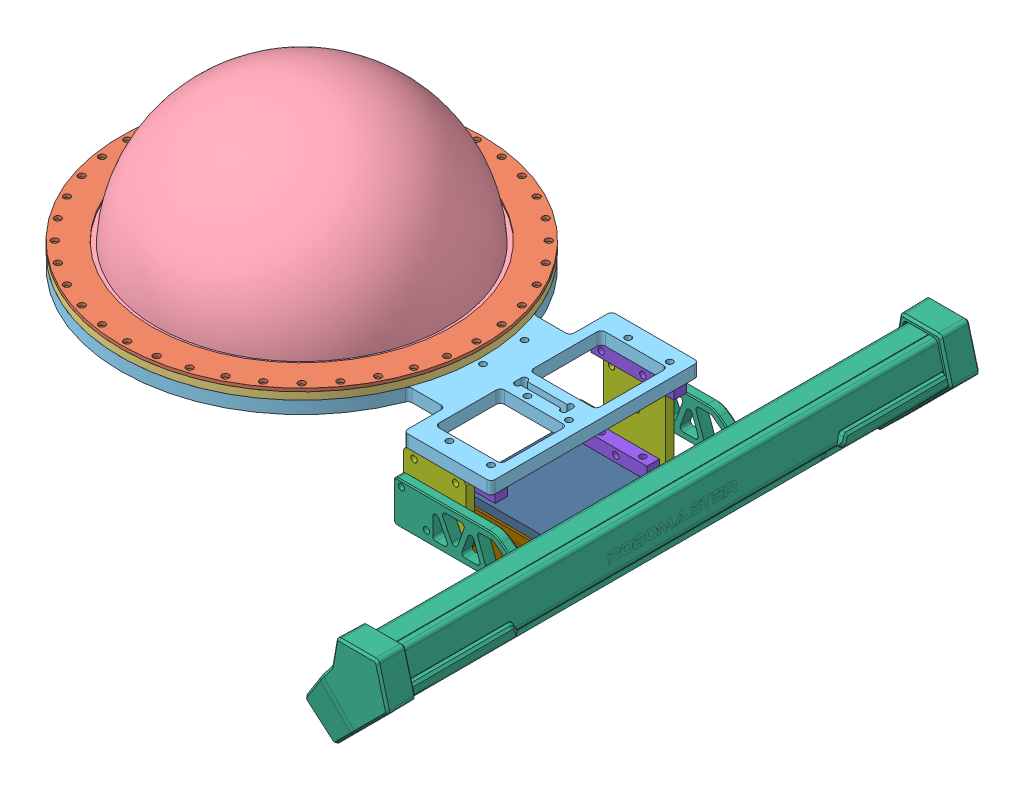
SolidWorks assembly MID-360模块, configuration 默认. Lengths in mm.
Overall size (293.47 159.5 285.15).
14 component instances, 11 part files, 41 mates.
Components (placement in the parent):
- pc球壳-1: pc球壳 [默认] at origin size (187 95 187) (hidden)
- mid-360-asm-1: mid-360-asm [默认] at (0 20.9171 0) size (72.74 69.72 66.83)
- pc球壳扣板-1: pc球壳扣板 [默认] x (0 0 -1) z (0 -1 0) size (174 174 1.5)
- pc球壳外挡圈-1: pc球壳外挡圈 [默认] at (0 -5 0) x (0.309017 0 -0.951057) z (0 1 0) size (174 174 3.5)
- 半球保护-100mm-1: 半球保护-100mm [默认] at (0 -5 0) x (0.993505 0 0.113788) z (0.113788 0 -0.993505) size (160 70 160)
- 360安装板-1: 360安装板 [默认] at (0 -5 0) x (1 0 0) z (0 -1 0) size (228 174 6)
- RM2019裁判系统灯条模块LI01-1: RM2019裁判系统灯条模块LI01 [默认] at (139.0893 -65.2494 -118.7555) x (0 0 -1) z (0 -1 0) size (285.15 84.96 50.25)
- 灯条安装板-1: 灯条安装板 [灯条安装] at (114 -26 48) size (30 30 4)
- 转接件上交-1: 转接件上交 [默认] at (99 -11 46) x (0 -1 0) z (1 0 0) size (6 6 40)
- 转接件上交-2: 转接件上交 [默认] at (99 -11 -40) x (0 -1 0) z (1 0 0) size (6 6 40)
- 灯条安装板-2: 灯条安装板 [uwb支撑] at (114 -26 -48) size (46 50 4)
- RM2019裁判系统定位模块UW01-1: RM2019裁判系统定位模块UW01 [默认] at (26.217 -93.7493 -13.6897) x (1 0 0) z (0 0 -1) size (45.56 33.5 81.86)
- uwb安装板-1: uwb安装板 [默认] at (106 -57 -19) x (1 0 0) z (0 -1 0) size (46 54 4)
- 转接件上交-3: 转接件上交 [默认] at (86 -51 -40) x (0 -1 0) z (1 0 0) size (6 6 40)
Mates (geometry in assembly coordinates):
- 同心1: concentric aligned: cylinder of pc球壳-1 through (0 0 0) axis (0 -1 0) radius 93.5; cylinder of pc球壳外挡圈-1 through (0 -1.5 0) axis (0 -1 0) radius 81
- 同心2: concentric anti-aligned: cylinder of pc球壳扣板-1 through (0 -1.5 0) axis (0 1 0) radius 72; cylinder of pc球壳外挡圈-1 through (0 -1.5 0) axis (0 -1 0) radius 87
- 重合3: coincident aligned: plane of mid-360-asm-1 through (0 -5 0) normal (0 -1 0); plane of pc球壳外挡圈-1 through (0 -5 0) normal (0 -1 0)
- 对称1: symmetric aligned: plane of mid-360-asm-1 through (-32.1003 8.6891 0) normal (0.999391 -0.034899 0); plane of mid-360-asm-1 through (32.1003 8.6891 0) normal (-0.999391 -0.034899 0)
- 对称2: symmetric aligned: plane of mid-360-asm-1 through (0 -3.0251 32.338) normal (0 -0.034899 0.999391); plane of mid-360-asm-1 through (0 -3.0251 -32.338) normal (0 -0.034899 -0.999391)
- 同心3: concentric: cylinder of pc球壳扣板-1 through (34.9459 9.0619 -73.0738) axis (0 1 0) radius 1.6; cylinder of pc球壳外挡圈-1 through (48.7107 3.5 -85.6126) axis (0 -1 0) radius 1.6
- 同心68: concentric: cylinder of pc球壳外挡圈-1 through (0 -1.5 0) axis (0 -1 0) radius 87; sphere of 半球保护-100mm-1
- 重合75: coincident aligned: plane of mid-360-asm-1 through (0 -5 0) normal (0 -1 0); plane of 半球保护-100mm-1 through (0 -5 0) normal (0 -1 0)
- 重合76: coincident anti-aligned: plane of pc球壳扣板-1 through (0 -1.5 0) normal (0 -1 0); plane of pc球壳外挡圈-1 through (0 -1.5 0) normal (0 1 0)
- 同心69: concentric anti-aligned: cylinder of pc球壳扣板-1 through (13.1405 -1.5 -82.9658) axis (0 1 0) radius 1.6; cylinder of pc球壳外挡圈-1 through (13.1405 -1.5 -82.9658) axis (0 -1 0) radius 1.6
- 重合77: coincident anti-aligned: plane of mid-360-asm-1 through (0 -5 0) normal (0 -1 0); plane of 360安装板-1 through (0 -5 0) normal (0 1 0)
- 同心70: concentric anti-aligned: cylinder of mid-360-asm-1 through (24 0.096 18) axis (0 -1 0) radius 1.25; cylinder of 360安装板-1 through (24 -11 18) axis (0 1 0) radius 1.55
- 同心71: concentric aligned: cone of mid-360-asm-1 through (24 -5 -18) axis (0 1 0); cylinder of 360安装板-1 through (24 -11 -18) axis (0 1 0) radius 1.55
- 平行1: parallel aligned: plane of 360安装板-1 through (0 -5 0) normal (0 1 0); plane of RM2019裁判系统灯条模块LI01-1 through (101 -21 54.5) normal (0 1 0)
- 宽度1: width aligned: plane of RM2019裁判系统灯条模块LI01-1 through (99.5 -43.8936 55) normal (0 0 1); plane of RM2019裁判系统灯条模块LI01-1 through (99.8 -43.8936 -55) normal (0 0 -1); plane of 360安装板-1 through (137 -117.9766 50) normal (0 0 1); plane of 360安装板-1 through (137 -117.9766 -50) normal (0 0 -1)
- 重合78: coincident anti-aligned: plane of RM2019裁判系统灯条模块LI01-1 through (99.8 -43.8936 50) normal (0 0 -1); plane of 灯条安装板-1 through (114 -26 50) normal (0 0 1)
- 重合79: coincident anti-aligned: plane of 360安装板-1 through (0 -11 0) normal (0 -1 0); plane of 灯条安装板-1 through (99 -11 50) normal (0 1 0)
- 重合80: coincident aligned: plane of pc球壳扣板-1 through (0 0 0) normal (1 0 0)
- 重合81: coincident anti-aligned: plane of pc球壳扣板-1 through (0 0 0) normal (0 -1 0)
- 重合82: coincident anti-aligned: plane of pc球壳扣板-1 through (0 0 0) normal (0 0 -1)
- 重合83: coincident aligned: plane of RM2019裁判系统灯条模块LI01-1 through (138 -41 54.5) normal (0 -1 0); plane of 灯条安装板-1 through (99 -41 50) normal (0 -1 0)
- 重合84: coincident aligned: plane of RM2019裁判系统灯条模块LI01-1 through (99 -39 54.5) normal (-1 0 0); plane of 灯条安装板-1 through (99 -41 50) normal (-1 0 0)
- 重合87: coincident anti-aligned: plane of 灯条安装板-1 through (114 -26 46) normal (0 0 -1); plane of 转接件上交-1 through (139 -11 46) normal (0 0 1)
- 重合88: coincident aligned: plane of 灯条安装板-1 through (99 -41 50) normal (-1 0 0); plane of 转接件上交-1 through (99 -11 46) normal (-1 0 0)
- 重合89: coincident anti-aligned: plane of 360安装板-1 through (0 -11 0) normal (0 -1 0); plane of 转接件上交-1 through (139 -11 46) normal (0 1 0)
- 重合90: coincident aligned: plane of 360安装板-1 through (99 -117.9766 -50) normal (-1 0 0); plane of 灯条安装板-1 through (99 -41 50) normal (-1 0 0)
- 重合91: coincident anti-aligned: plane of 转接件上交-2 through (139 -11 -46) normal (0 0 -1); plane of 灯条安装板-2 through (114 -26 -46) normal (0 0 1)
- 重合92: coincident anti-aligned: plane of RM2019裁判系统灯条模块LI01-1 through (99.5 -43.8936 -50) normal (0 0 1); plane of 灯条安装板-2 through (114 -26 -50) normal (0 0 -1)
- 重合93: coincident anti-aligned: plane of 360安装板-1 through (0 -11 0) normal (0 -1 0); plane of 转接件上交-2 through (139 -11 -40) normal (0 1 0)
- 重合94: coincident aligned: plane of 360安装板-1 through (99 -117.9766 -50) normal (-1 0 0); plane of 灯条安装板-2 through (99 -41 -46) normal (-1 0 0)
- 重合95: coincident anti-aligned: plane of 360安装板-1 through (0 -11 0) normal (0 -1 0); plane of 灯条安装板-2 through (99 -11 -46) normal (0 1 0)
- 重合96: coincident aligned: plane of 转接件上交-2 through (99 -11 -40) normal (-1 0 0); plane of 灯条安装板-2 through (99 -41 -46) normal (-1 0 0)
- 重合97: coincident anti-aligned: plane of 灯条安装板-2 through (99 -61 -86.0555) normal (0 -1 0); plane of RM2019裁判系统定位模块UW01-1 through (106 -61 -13.6897) normal (0 1 0)
- 平行3: parallel aligned: plane of 灯条安装板-2 through (83 -61 -70) normal (-1 0 0); plane of RM2019裁判系统定位模块UW01-1 through (83.25 -129.3467 -31.1897) normal (-1 0 0)
- 重合98: coincident anti-aligned: plane of RM2019裁判系统定位模块UW01-1 through (106 -61 -13.6897) normal (0 1 0); plane of uwb安装板-1 through (106 -61 -19) normal (0 -1 0)
- 重合99: coincident anti-aligned: plane of 灯条安装板-2 through (114 -26 -46) normal (0 0 1); plane of uwb安装板-1 through (83 -61 -46) normal (0 0 -1)
- 重合100: coincident aligned: plane of 灯条安装板-2 through (129 -41 -46) normal (1 0 0); plane of uwb安装板-1 through (129 -61 -46) normal (1 0 0)
- 重合101: coincident anti-aligned: plane of 灯条安装板-2 through (114 -26 -46) normal (0 0 1); plane of 转接件上交-3 through (126 -51 -46) normal (0 0 -1)
- 重合102: coincident anti-aligned: plane of uwb安装板-1 through (106 -57 -19) normal (0 1 0); plane of 转接件上交-3 through (126 -57 -40) normal (0 -1 0)
- 宽度2: width aligned: plane of 灯条安装板-2 through (83 -61 -70) normal (-1 0 0); plane of 转接件上交-3 through (129 -41 -46) normal (1 0 0); plane of 灯条安装板-2 through (86 -51 -40) normal (-1 0 0); plane of 转接件上交-3 through (126 -51 -40) normal (1 0 0)
- 宽度3: width aligned: plane of RM2019裁判系统定位模块UW01-1 through (83.25 -129.3467 -31.1897) normal (-1 0 0); plane of uwb安装板-1 through (128.75 -129.3467 3.8103) normal (1 0 0); plane of RM2019裁判系统定位模块UW01-1 through (83 -61 -46) normal (-1 0 0); plane of uwb安装板-1 through (129 -61 -46) normal (1 0 0)
